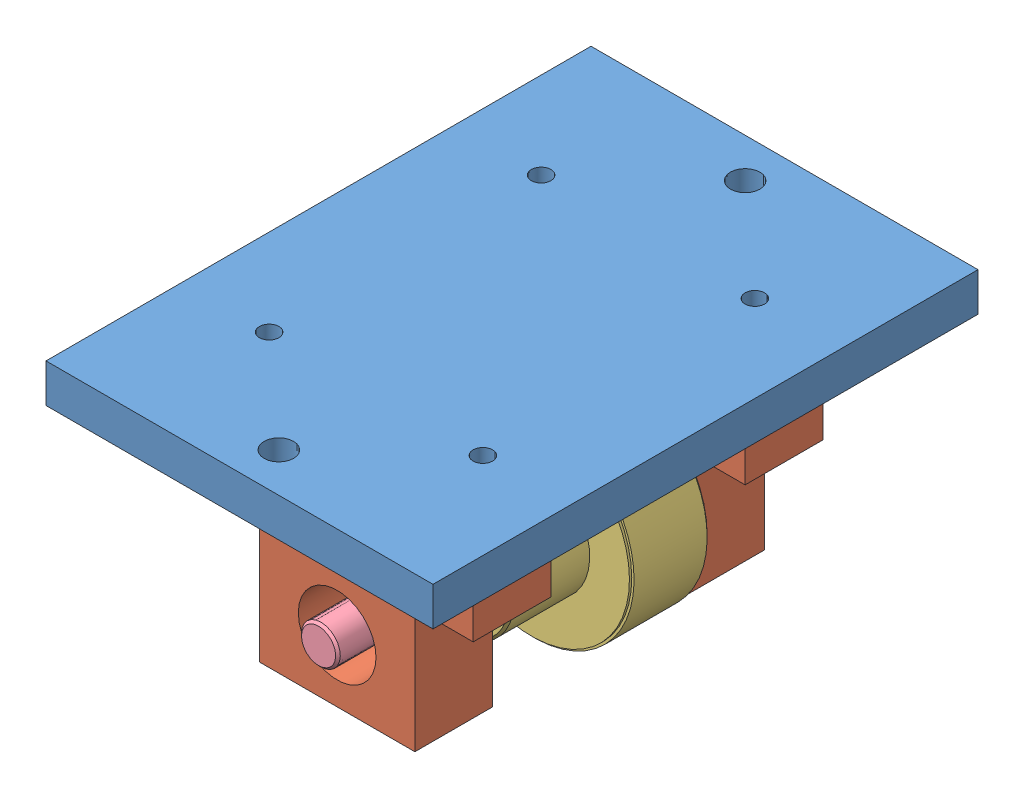
SolidWorks assembly Assem1, configuration Default. Lengths in mm.
Overall size (63.25 48.02 89.08).
5 component instances, 4 part files, 13 mates.
Components (placement in the parent):
- Q1 P1-1: Q1 P1 [Default] at (-92.66 4.3275 71.6604) size (63.25 6.32 89.08)
- Q1 P3-1: Q1 P3 [Default] at (-83.26 5.6975 11.2454) x (0 0 -1) z (-1 0 0) size (12.7 36.2 44.45)
- Q1 P3-2: Q1 P3 [Default] at (-38.805 5.6975 42.9954) x (0 0 1) z (1 0 0) size (12.7 36.2 44.45)
- Q1 P4-1: Q1 P4 [Default] at (-61.035 -20.3425 11.2454) x (-0.999228 -0.039276 0) z (-0.039276 0.999228 0) size (32.8 25.4 32.8)
- Q1 P5-1: Q1 P5 [Default] at (-61.035 -20.3425 58.3572) x (0.71262 0.70155 0) z (0 0 1) size (6.35 6.35 63.57)
Mates (geometry in assembly coordinates):
- Concentric1: concentric anti-aligned: circle of Q1 P1-1; circle of Q1 P3-1
- Parallel1: parallel anti-aligned: plane of Q1 P1-1 through (-92.66 5.6975 71.6604) normal (0 -1 0); plane of Q1 P3-1 through (-83.26 5.6975 11.2454) normal (0 1 0)
- Parallel2: parallel anti-aligned: plane of Q1 P1-1 through (-86.395 5.6975 -4.6546) normal (0 0 1); plane of Q1 P3-1 through (-83.26 -10.1825 -1.4546) normal (0 0 -1)
- Coincident2: coincident anti-aligned: plane of Q1 P1-1 through (-92.66 5.6975 71.6604) normal (0 -1 0); plane of Q1 P3-1 through (-83.26 5.6975 11.2454) normal (0 1 0)
- Parallel3: parallel anti-aligned: plane of Q1 P1-1 through (-86.395 5.6975 58.8954) normal (0 0 -1); plane of Q1 P3-2 through (-38.805 -10.1825 55.6954) normal (0 0 1)
- Parallel4: parallel anti-aligned: plane of Q1 P1-1 through (-92.66 5.6975 71.6604) normal (0 -1 0); plane of Q1 P3-2 through (-38.805 5.6975 42.9954) normal (0 1 0)
- Concentric8: concentric anti-aligned: circle of Q1 P1-1; circle of Q1 P3-2
- Coincident5: coincident anti-aligned: plane of Q1 P1-1 through (-92.66 5.6975 71.6604) normal (0 -1 0); plane of Q1 P3-2 through (-38.805 5.6975 42.9954) normal (0 1 0)
- Coincident6: coincident anti-aligned: plane of Q1 P3-1 through (-83.26 -10.1825 11.2454) normal (0 0 1); plane of Q1 P4-1 through (-61.035 -20.3425 11.2454) normal (0 0 -1)
- Concentric9: concentric aligned: cylinder of Q1 P3-2 through (-61.035 -20.3425 42.9954) axis (0 0 1) radius 6.35; cylinder of Q1 P4-1 through (-61.035 -20.3425 17.5954) axis (0 0 1) radius 3.19
- Parallel5: parallel anti-aligned: plane of Q1 P4-1 through (-61.035 -20.3425 36.6454) normal (0 0 1); plane of Q1 P5-1 through (-61.035 -20.3425 -4.8328) normal (0 0 -1)
- Concentric10: concentric aligned: cylinder of Q1 P3-2 through (-61.035 -20.3425 42.9954) axis (0 0 1) radius 6.35; cylinder of Q1 P5-1 through (-61.035 -20.3425 -4.4528) axis (0 0 1) radius 3.175
- Lock2: lock: unknown of Q1 P4-1; unknown of Q1 P5-1
